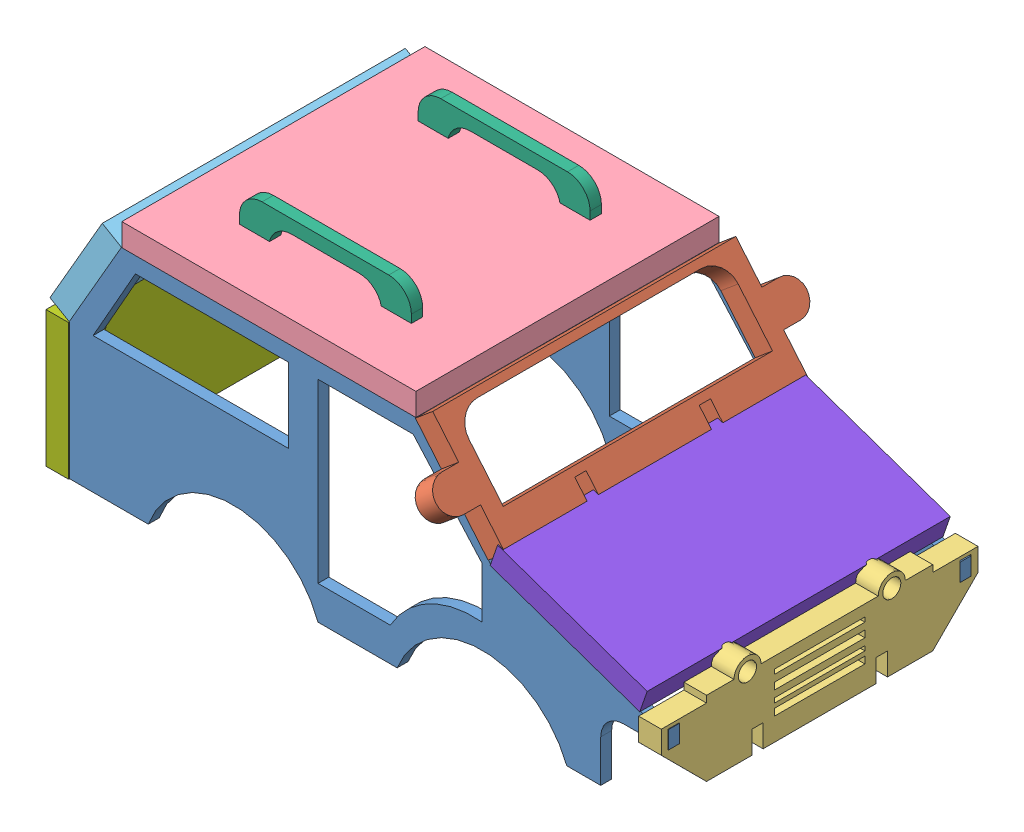
SolidWorks assembly CarroAlan2, configuration Predeterminado. Lengths in mm.
Overall size (274.83 123.89 164).
12 component instances, 9 part files, 17 mates.
Components (placement in the parent):
- CarroAlan-1: CarroAlan [Predeterminado] at origin size (265.01 106.43 164)
  - LateralAlan-1: LateralAlan [Predeterminado] at (-8.8589 -71.3997 258.1976) size (265.01 100 4.8)
  - ParabrisasAlan-1: ParabrisasAlan [Predeterminado] at (56.5349 -3.274 324.8244) x (0 0 1) z (-0.766044 -0.642788 0) size (164 50 10)
  - ParrillaAlan-1: ParrillaAlan [Predeterminado] at (118.6217 -62.966 324.9976) x (0 0 -1) z (1 0 0) size (140 39.02 10)
  - Pieza2^CarroAlan-1: Pieza2^CarroAlan [Predeterminado] at (-8.8589 -71.3997 258.1976) x (-1 0 0) z (0 0 -1) (virtual)
  - LateralAlan-3: LateralAlan [Predeterminado] at (-8.8589 -71.0654 386.9855) size (265.01 100 4.8)
- TechoAlan-1: TechoAlan [Predeterminado] at (-113.0719 28.9346 391.7855) size (130 10 134)
- TraseroAlan-3: TraseroAlan [Predeterminado] at (-136.1719 -11.0758 257.7855) x (0 0 1) z (-0.5 -0.866025 0) size (134 10 46.2)
- PatasAlan-3: PatasAlan [Predeterminado] at (-86.0719 28.9346 361.7855) x (1 0 0) z (0 -1 0) size (76 5 23.55)
- PatasAlan-4: PatasAlan [Predeterminado] at (-86.0719 28.9346 282.7855) x (1 0 0) z (0 -1 0) size (76 5 23.55)
- CajuelaAlan-1: CajuelaAlan [Predeterminado] at (-136.1719 -71.0758 258.1976) x (0 0 1) z (-1 0 0) size (134 60 10)
- CofreAlan2-1: CofreAlan2 [Predeterminado] at (50.1661 -10.9018 258.1976) x (0 0 1) z (-0.944746 0.327803 0) size (134 10 70)
Mates (geometry in assembly coordinates):
- Coincidente3: coincident aligned: line of CarroAlan-1/LateralAlan-3 through (-113.2649 28.9346 391.7855) axis (1 0 0); line of TechoAlan-1 through (-113.0719 28.9346 391.7855) axis (1 0 0)
- Paralelo3: parallel anti-aligned: plane of CarroAlan-1/LateralAlan-3 through (-8.8589 -71.0654 391.7855) normal (0 0 1); plane of TraseroAlan-3 through (-144.8322 -6.0758 257.7855) normal (0 0 -1)
- Coincidente8: coincident aligned: plane of CarroAlan-1/LateralAlan-3 through (-8.8589 -71.0654 391.7855) normal (0 0 1); plane of TraseroAlan-3 through (-144.8322 -6.0758 391.7855) normal (0 0 1)
- Coincidente12: coincident anti-aligned: plane of CarroAlan-1/LateralAlan-1 through (-130.4647 -1.1905 262.9976) normal (-0.866025 0.5 0); plane of TraseroAlan-3 through (-136.1719 -11.0758 257.7855) normal (0.866025 -0.5 0)
- Paralelo5: parallel anti-aligned: plane of CarroAlan-1/LateralAlan-1 through (-8.8589 28.6003 262.9976) normal (0 1 0); plane of TechoAlan-1 through (-113.0719 28.9346 391.7855) normal (0 -1 0)
- Paralelo6: parallel aligned: plane of CarroAlan-1/LateralAlan-1 through (-8.8589 -71.3997 258.1976) normal (0 0 -1); plane of TechoAlan-1 through (-113.0719 38.9346 257.7855) normal (0 0 -1)
- Coincidente37: coincident anti-aligned: line of TechoAlan-1 through (-113.0719 28.9346 257.7855) axis (0 0 1); line of TraseroAlan-3 through (-113.0719 28.9346 391.7855) axis (0 0 -1)
- Coincidente38: coincident anti-aligned: plane of TechoAlan-1 through (-10.0719 38.9346 361.7855) normal (0 0 1); plane of PatasAlan-3 through (-76.0719 42.4896 361.7855) normal (0 0 -1)
- Coincidente39: coincident anti-aligned: plane of TechoAlan-1 through (-86.0719 38.9346 366.7855) normal (1 0 0); plane of PatasAlan-3 through (-86.0719 28.9346 366.7855) normal (-1 0 0)
- Coincidente40: coincident aligned: plane of TechoAlan-1 through (-113.0719 28.9346 391.7855) normal (0 -1 0); plane of PatasAlan-3 through (-86.0719 28.9346 366.7855) normal (0 -1 0)
- Coincidente41: coincident anti-aligned: plane of TechoAlan-1 through (-86.0719 38.9346 287.7855) normal (0 0 -1); plane of PatasAlan-4 through (-76.0719 42.4896 287.7855) normal (0 0 1)
- Coincidente42: coincident anti-aligned: plane of TechoAlan-1 through (-86.0719 38.9346 282.7855) normal (1 0 0); plane of PatasAlan-4 through (-86.0719 28.9346 287.7855) normal (-1 0 0)
- Coincidente43: coincident aligned: plane of TechoAlan-1 through (-113.0719 28.9346 391.7855) normal (0 -1 0); plane of PatasAlan-4 through (-86.0719 28.9346 287.7855) normal (0 -1 0)
- Coincidente44: coincident anti-aligned: line of TraseroAlan-3 through (-136.1719 -11.0758 257.7855) axis (0 0 1); line of CajuelaAlan-1 through (-136.1719 -11.0758 392.1976) axis (0 0 -1)
- Paralelo8: parallel: line of CarroAlan-1/LateralAlan-3 through (-136.3589 -71.0654 391.7855) axis (0 1 0); plane of CajuelaAlan-1 through (-146.1719 -71.0758 258.1976) normal (-1 0 0)
- Coincidente60: coincident anti-aligned: plane of CarroAlan-1/LateralAlan-3 through (16.1157 0.9128 391.7855) normal (0.327803 0.944746 0); plane of CofreAlan2-1 through (50.1661 -10.9018 258.1976) normal (-0.327803 -0.944746 0)
- Coincidente63: coincident aligned: plane of CarroAlan-1/LateralAlan-1 through (-8.8589 -71.3997 258.1976) normal (0 0 -1); plane of CofreAlan2-1 through (53.4442 -1.4544 258.1976) normal (0 0 -1)
